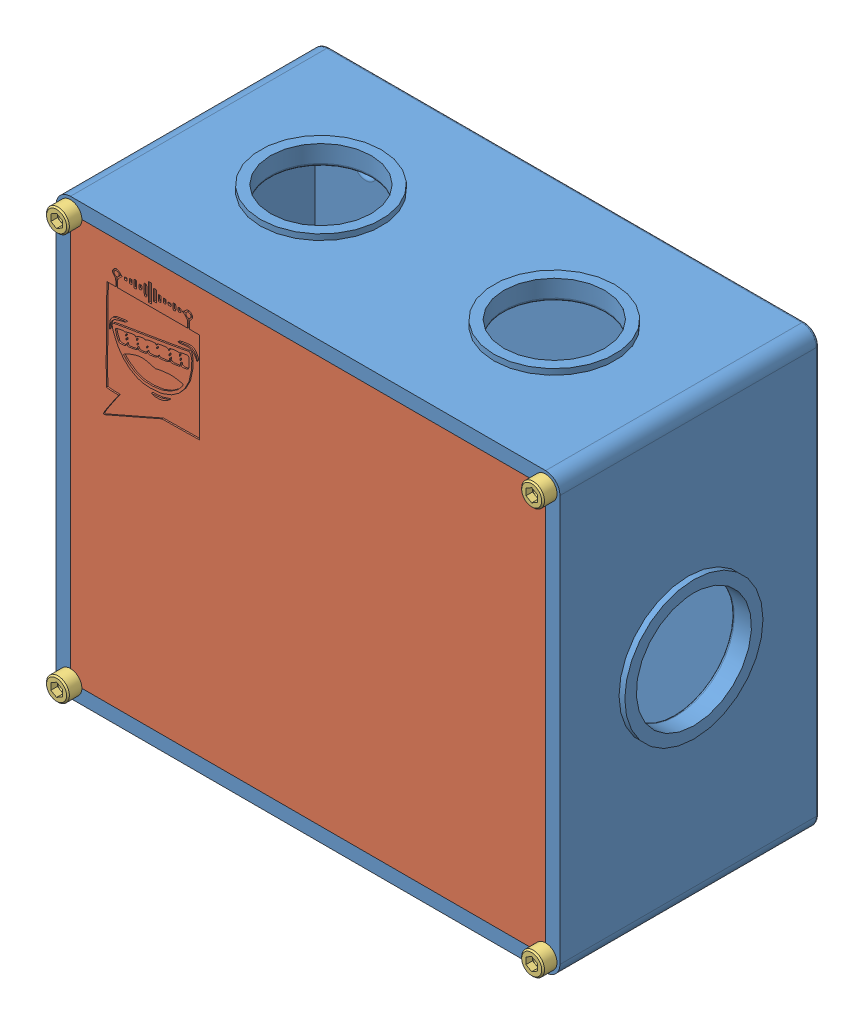
SolidWorks assembly boitederivationASM, configuration Défaut. Lengths in mm.
Overall size (179 155 94.83).
6 component instances, 3 part files, 11 mates.
Components (placement in the parent):
- boitederivation-1: boitederivation [Défaut] at (-83.776 -76.2045 134) size (179 155 90)
- couvercle-1: couvercle [Défaut] at (-78.776 -71.2045 221) size (165 141 3)
- socket head cap screw_ai-1: socket head cap screw_ai [HX-SHCS 0.19-32x0.75x0.75-N] at (-78.776 69.7955 228.826) x (0 0 -1) z (1 0 0) size (23.88 7.94 7.94)
- socket head cap screw_ai-2: socket head cap screw_ai [HX-SHCS 0.19-32x0.75x0.75-N] at (86.224 69.7955 228.826) x (0 0 -1) z (1 0 0) size (23.88 7.94 7.94)
- socket head cap screw_ai-3: socket head cap screw_ai [HX-SHCS 0.19-32x0.75x0.75-N] at (86.224 -71.2045 228.826) x (0 0 -1) z (1 0 0) size (23.88 7.94 7.94)
- socket head cap screw_ai-4: socket head cap screw_ai [HX-SHCS 0.19-32x0.75x0.75-N] at (-78.776 -71.2045 228.826) x (0 0 -1) z (1 0 0) size (23.88 7.94 7.94)
Mates (geometry in assembly coordinates):
- Coïncidente1: coincident: plane of boitederivation-1 through (86.224 -71.2045 224) normal (0 0 1); plane of couvercle-1 through (-78.776 -71.2045 224) normal (0 0 1)
- Coïncidente3: coincident: plane of boitederivation-1 through (-78.776 -71.2045 224) normal (1 0 0); plane of couvercle-1 through (-78.776 -71.2045 224) normal (-1 0 0)
- Coïncidente4: coincident: plane of boitederivation-1 through (-78.776 69.7955 224) normal (0 -1 0); plane of couvercle-1 through (-78.776 69.7955 224) normal (0 1 0)
- Coaxiale11: concentric: cylinder of boitederivation-1 through (-78.776 69.7955 206) axis (0 0 1) radius 3; cylinder of socket head cap screw_ai-1 through (-78.776 69.7955 260.576) axis (0 0 1) radius 2.413
- Coïncidente51: coincident: plane of boitederivation-1 through (86.224 -71.2045 224) normal (0 0 1); plane of socket head cap screw_ai-1 through (-78.776 73.7642 224) normal (0 0 -1)
- Coaxiale21: concentric: cylinder of boitederivation-1 through (86.224 69.7955 206) axis (0 0 1) radius 3; cylinder of socket head cap screw_ai-2 through (86.224 69.7955 260.576) axis (0 0 1) radius 2.413
- Coïncidente61: coincident: plane of boitederivation-1 through (86.224 -71.2045 224) normal (0 0 1); plane of socket head cap screw_ai-2 through (86.224 73.7642 224) normal (0 0 -1)
- Coaxiale31: concentric: cylinder of boitederivation-1 through (86.224 -71.2045 206) axis (0 0 1) radius 3; cylinder of socket head cap screw_ai-3 through (86.224 -71.2045 260.576) axis (0 0 1) radius 2.413
- Coïncidente71: coincident: plane of boitederivation-1 through (86.224 -71.2045 224) normal (0 0 1); plane of socket head cap screw_ai-3 through (86.224 -67.2358 224) normal (0 0 -1)
- Coaxiale41: concentric: cylinder of boitederivation-1 through (-78.776 -71.2045 206) axis (0 0 1) radius 3; cylinder of socket head cap screw_ai-4 through (-78.776 -71.2045 260.576) axis (0 0 1) radius 2.413
- Coïncidente81: coincident: plane of boitederivation-1 through (86.224 -71.2045 224) normal (0 0 1); plane of socket head cap screw_ai-4 through (-78.776 -67.2358 224) normal (0 0 -1)
